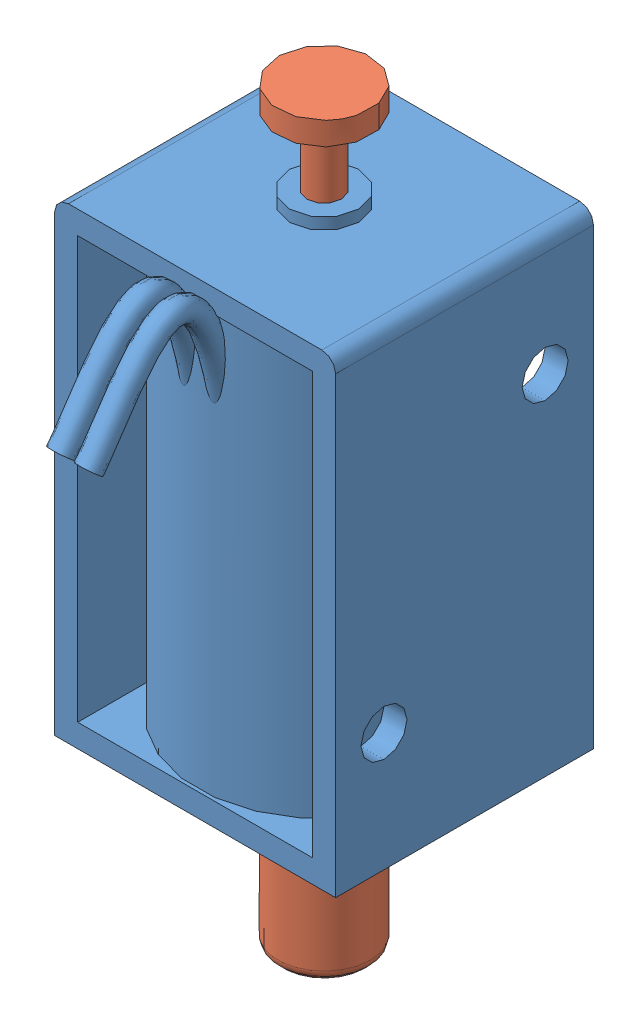
SolidWorks assembly H10-0420-PUSH-12.SLDALASM, configuration Default. Lengths in mm.
Overall size (12.2 32.5 16.82).
2 component instances, 2 part files, 2 mates.
Components (placement in the parent):
- H10-0420-PUSH-12_body-1: H10-0420-PUSH-12_body [Default] at origin size (12.2 20.8 16.82)
- H10-0420-PUSH-12_rod-1: H10-0420-PUSH-12_rod [Default] at (6.1 24.8 -5.6) x (-0.488187 0 0.872739) z (0.872739 0 0.488187) size (4 32.5 4)
Mates (geometry in assembly coordinates):
- 同心円2: concentric aligned: cylinder of H10-0420-PUSH-12_body-1 through (6.1 0 -5.6) axis (0 1 0) radius 0.75; cylinder of H10-0420-PUSH-12_rod-1 through (6.1 -7.7 -5.6) axis (0 1 0) radius 2
- 距離1: distance = 4.5 mm aligned: plane of H10-0420-PUSH-12_body-1 through (0 20.3 0) normal (0 1 0); plane of H10-0420-PUSH-12_rod-1 through (6.1 24.8 -5.6) normal (0 1 0)
